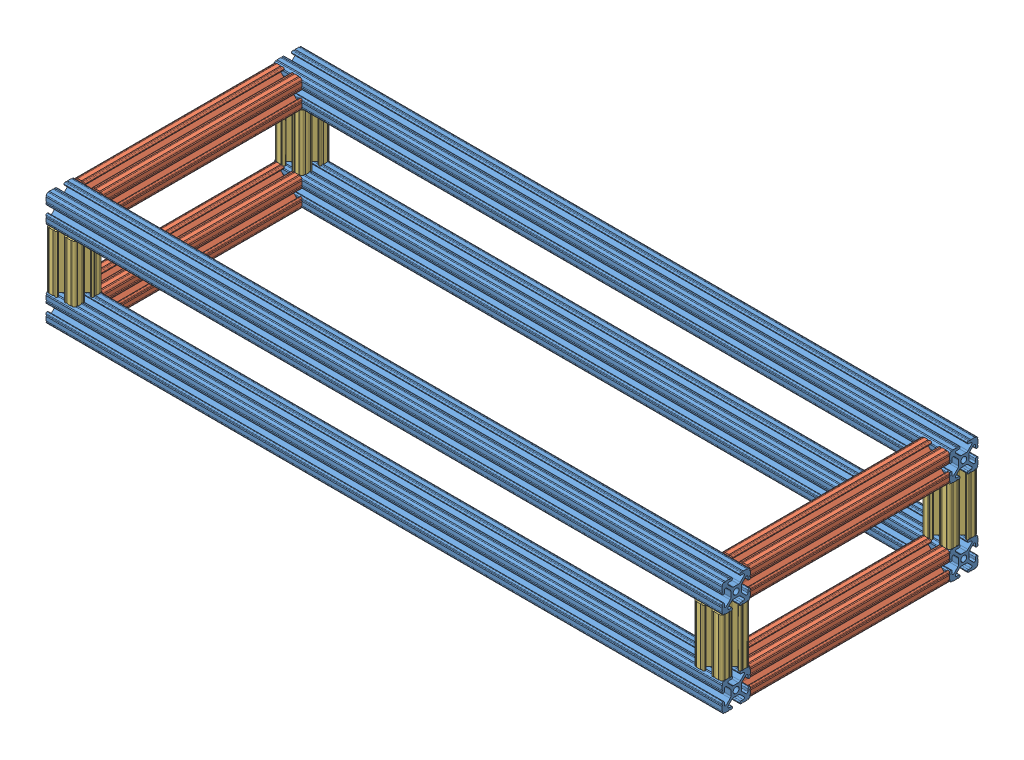
SolidWorks assembly ATLAS_full_Skeleton, configuration Default. Lengths in mm.
Overall size (603.25 101.6 228.6).
14 component instances, 3 part files, 30 mates.
Components (placement in the parent):
- ATLAS_Skeleton-1: ATLAS_Skeleton [Default] at (886.4881 399.8543 619.7926) size (603.25 25.4 228.6)
  - 47065T209_T-Slotted-23.75-1: 47065T209_T-Slotted-23.75 [47065T209] at (-735.7295 -98.2501 251.747) x (0 0 -1) z (1 0 0) size (25.4 25.4 603.25)
  - 47065T411_T-Slotted_9in-1: 47065T411_T-Slotted_9in [47065T411] at (-449.9795 -98.2501 213.647) size (25.4 25.4 177.8)
  - 47065T411_T-Slotted_9in-2: 47065T411_T-Slotted_9in [47065T411] at (-1027.8295 -98.2501 213.647) size (25.4 25.4 177.8)
  - 47065T209_T-Slotted-23.75-3: 47065T209_T-Slotted-23.75 [47065T209] at (-735.7295 -98.2501 48.547) x (0 0 -1) z (1 0 0) size (25.4 25.4 603.25)
- ATLAS_Skeleton-2: ATLAS_Skeleton [Default] at (886.4881 323.6543 619.7926) size (603.25 25.4 228.6)
  - 47065T209_T-Slotted-23.75-1: 47065T209_T-Slotted-23.75 [47065T209] at (-735.7295 -98.2501 251.747) x (0 0 -1) z (1 0 0) size (25.4 25.4 603.25)
  - 47065T411_T-Slotted_9in-1: 47065T411_T-Slotted_9in [47065T411] at (-449.9795 -98.2501 213.647) size (25.4 25.4 177.8)
  - 47065T411_T-Slotted_9in-2: 47065T411_T-Slotted_9in [47065T411] at (-1027.8295 -98.2501 213.647) size (25.4 25.4 177.8)
  - 47065T209_T-Slotted-23.75-3: 47065T209_T-Slotted-23.75 [47065T209] at (-735.7295 -98.2501 48.547) x (0 0 -1) z (1 0 0) size (25.4 25.4 603.25)
- 47065T553_T-Slotted_2in-1: 47065T553_T-Slotted_2in [47065T553] at (436.5086 314.3042 871.5396) x (1 0 0) z (0 1 0) size (25.4 25.4 50.8)
- 47065T553_T-Slotted_2in-2: 47065T553_T-Slotted_2in [47065T553] at (-141.3414 212.7042 668.3396) x (1 0 0) z (0 -1 0) size (25.4 25.4 50.8)
- 47065T553_T-Slotted_2in-3: 47065T553_T-Slotted_2in [47065T553] at (-141.3414 314.3042 871.5396) x (1 0 0) z (0 1 0) size (25.4 25.4 50.8)
- 47065T553_T-Slotted_2in-4: 47065T553_T-Slotted_2in [47065T553] at (436.5086 314.3042 668.3396) x (1 0 0) z (0 1 0) size (25.4 25.4 50.8)
Mates (geometry in assembly coordinates):
- Coincident1: coincident anti-aligned: plane of ATLAS_Skeleton-1/47065T209_T-Slotted-23.75-3 through (285.9215 391.1779 449.7769) normal (0 -1 0); plane of 47065T553_T-Slotted_2in-4 through (254.1715 391.1779 437.6195) normal (0 1 0)
- Coincident2: coincident aligned: plane of ATLAS_Skeleton-1/47065T209_T-Slotted-23.75-3 through (279.5715 431.4786 466.6672) normal (1 0 0); plane of 47065T553_T-Slotted_2in-4 through (279.5715 492.7779 449.7769) normal (1 0 0)
- Coincident3: coincident aligned: plane of ATLAS_Skeleton-1/47065T209_T-Slotted-23.75-3 through (285.9215 399.6875 441.2672) normal (0 0 -1); plane of 47065T553_T-Slotted_2in-4 through (271.0619 492.7779 441.2672) normal (0 0 -1)
- Coincident4: coincident aligned: plane of ATLAS_Skeleton-1/47065T209_T-Slotted-23.75-3 through (285.9215 399.6875 441.2672) normal (0 0 -1); plane of 47065T553_T-Slotted_2in-4 through (262.6812 492.7779 441.2672) normal (0 0 -1)
- Coincident5: coincident aligned: plane of ATLAS_Skeleton-1/47065T209_T-Slotted-23.75-3 through (279.5715 431.4786 466.6672) normal (1 0 0); plane of 47065T553_T-Slotted_2in-4 through (279.5715 492.7779 449.7769) normal (1 0 0)
- Coincident6: coincident anti-aligned: plane of ATLAS_Skeleton-1/47065T209_T-Slotted-23.75-1 through (285.9215 391.1779 661.3576) normal (0 -1 0); plane of 47065T553_T-Slotted_2in-1 through (254.1715 391.1779 640.8195) normal (0 1 0)
- Coincident7: coincident aligned: plane of ATLAS_Skeleton-1/47065T209_T-Slotted-23.75-1 through (285.9215 399.6875 669.8672) normal (0 0 1); plane of 47065T553_T-Slotted_2in-1 through (271.0619 492.7779 669.8672) normal (0 0 1)
- Coincident8: coincident aligned: plane of ATLAS_Skeleton-1/47065T209_T-Slotted-23.75-1 through (285.9215 399.6875 669.8672) normal (0 0 1); plane of 47065T553_T-Slotted_2in-1 through (271.0619 492.7779 669.8672) normal (0 0 1)
- Coincident9: coincident aligned: plane of ATLAS_Skeleton-1/47065T209_T-Slotted-23.75-1 through (279.5715 431.4786 669.8672) normal (1 0 0); plane of 47065T553_T-Slotted_2in-1 through (279.5715 492.7779 661.3576) normal (1 0 0)
- Coincident10: coincident aligned: plane of ATLAS_Skeleton-1/47065T209_T-Slotted-23.75-1 through (279.5715 431.4786 669.8672) normal (1 0 0); plane of 47065T553_T-Slotted_2in-1 through (279.5715 492.7779 652.9769) normal (1 0 0)
- Coincident11: coincident anti-aligned: plane of ATLAS_Skeleton-1/47065T209_T-Slotted-23.75-3 through (285.9215 391.1779 449.7769) normal (0 -1 0); plane of 47065T553_T-Slotted_2in-2 through (-306.7881 391.1779 442.2064) normal (0 1 0)
- Coincident12: coincident aligned: plane of ATLAS_Skeleton-1/47065T209_T-Slotted-23.75-3 through (285.9215 408.0683 441.2672) normal (0 0 -1); plane of 47065T553_T-Slotted_2in-2 through (-315.1688 238.7779 441.2672) normal (0 0 -1)
- Coincident13: coincident aligned: plane of ATLAS_Skeleton-1/47065T209_T-Slotted-23.75-3 through (-323.6785 392.1171 449.7769) normal (-1 0 0); plane of 47065T553_T-Slotted_2in-2 through (-323.6785 238.7779 458.1576) normal (-1 0 0)
- Coincident14: coincident aligned: plane of ATLAS_Skeleton-1/47065T209_T-Slotted-23.75-3 through (-323.6785 392.1171 449.7769) normal (-1 0 0); plane of 47065T553_T-Slotted_2in-2 through (-323.6785 238.7779 449.7769) normal (-1 0 0)
- Coincident15: coincident aligned: plane of ATLAS_Skeleton-1/47065T209_T-Slotted-23.75-3 through (285.9215 399.6875 441.2672) normal (0 0 -1); plane of 47065T553_T-Slotted_2in-2 through (-306.7881 238.7779 441.2672) normal (0 0 -1)
- Coincident16: coincident anti-aligned: plane of ATLAS_Skeleton-1/47065T209_T-Slotted-23.75-1 through (285.9215 391.1779 652.9769) normal (0 -1 0); plane of 47065T553_T-Slotted_2in-3 through (-323.6785 391.1779 640.8195) normal (0 1 0)
- Coincident17: coincident aligned: plane of ATLAS_Skeleton-1/47065T411_T-Slotted_9in-2 through (-323.6785 399.6875 771.4672) normal (-1 0 0); plane of 47065T553_T-Slotted_2in-3 through (-323.6785 492.7779 661.3576) normal (-1 0 0)
- Coincident18: coincident aligned: plane of ATLAS_Skeleton-1/47065T411_T-Slotted_9in-2 through (-323.6785 399.6875 771.4672) normal (-1 0 0); plane of 47065T553_T-Slotted_2in-3 through (-323.6785 492.7779 652.9769) normal (-1 0 0)
- Coincident19: coincident aligned: plane of ATLAS_Skeleton-1/47065T209_T-Slotted-23.75-1 through (285.9215 399.6875 669.8672) normal (0 0 1); plane of 47065T553_T-Slotted_2in-3 through (-315.1688 492.7779 669.8672) normal (0 0 1)
- Coincident20: coincident aligned: plane of ATLAS_Skeleton-1/47065T209_T-Slotted-23.75-1 through (285.9215 399.6875 669.8672) normal (0 0 1); plane of 47065T553_T-Slotted_2in-3 through (-306.7881 492.7779 669.8672) normal (0 0 1)
- Coincident21: coincident aligned: plane of ATLAS_Skeleton-2/47065T209_T-Slotted-23.75-3 through (-323.6785 315.9171 449.7769) normal (-1 0 0); plane of 47065T553_T-Slotted_2in-2 through (-323.6785 238.7779 449.7769) normal (-1 0 0)
- Coincident22: coincident anti-aligned: plane of ATLAS_Skeleton-2/47065T411_T-Slotted_9in-2 through (-315.1688 340.3779 771.4672) normal (0 1 0); plane of 47065T553_T-Slotted_2in-2 through (-323.6785 340.3779 470.315) normal (0 -1 0)
- Coincident23: coincident aligned: plane of ATLAS_Skeleton-2/47065T209_T-Slotted-23.75-1 through (285.9215 331.8683 669.8672) normal (0 0 1); plane of 47065T553_T-Slotted_2in-3 through (-315.1688 492.7779 669.8672) normal (0 0 1)
- Coincident24: coincident aligned: plane of ATLAS_Skeleton-2/47065T209_T-Slotted-23.75-1 through (279.5715 355.2786 669.8672) normal (1 0 0); plane of 47065T553_T-Slotted_2in-1 through (279.5715 492.7779 661.3576) normal (1 0 0)
- Coincident25: coincident aligned: plane of ATLAS_Skeleton-2/47065T209_T-Slotted-23.75-3 through (285.9215 331.8683 441.2672) normal (0 0 -1); plane of 47065T553_T-Slotted_2in-4 through (271.0619 492.7779 441.2672) normal (0 0 -1)
- Coincident26: coincident aligned: plane of ATLAS_Skeleton-2/47065T209_T-Slotted-23.75-3 through (285.9215 331.8683 441.2672) normal (0 0 -1); plane of 47065T553_T-Slotted_2in-4 through (262.6812 492.7779 441.2672) normal (0 0 -1)
- Coincident27: coincident aligned: plane of ATLAS_Skeleton-2/47065T209_T-Slotted-23.75-3 through (285.9215 331.8683 441.2672) normal (0 0 -1); plane of 47065T553_T-Slotted_2in-2 through (-306.7881 238.7779 441.2672) normal (0 0 -1)
- Coincident28: coincident aligned: plane of ATLAS_Skeleton-2/47065T209_T-Slotted-23.75-3 through (285.9215 331.8683 441.2672) normal (0 0 -1); plane of 47065T553_T-Slotted_2in-2 through (-315.1688 238.7779 441.2672) normal (0 0 -1)
- Coincident29: coincident aligned: plane of ATLAS_Skeleton-2/47065T209_T-Slotted-23.75-3 through (-323.6785 315.9171 449.7769) normal (-1 0 0); plane of 47065T553_T-Slotted_2in-2 through (-323.6785 238.7779 449.7769) normal (-1 0 0)
- Coincident30: coincident aligned: plane of ATLAS_Skeleton-2/47065T209_T-Slotted-23.75-3 through (-323.6785 315.9171 449.7769) normal (-1 0 0); plane of 47065T553_T-Slotted_2in-2 through (-323.6785 238.7779 458.1576) normal (-1 0 0)
